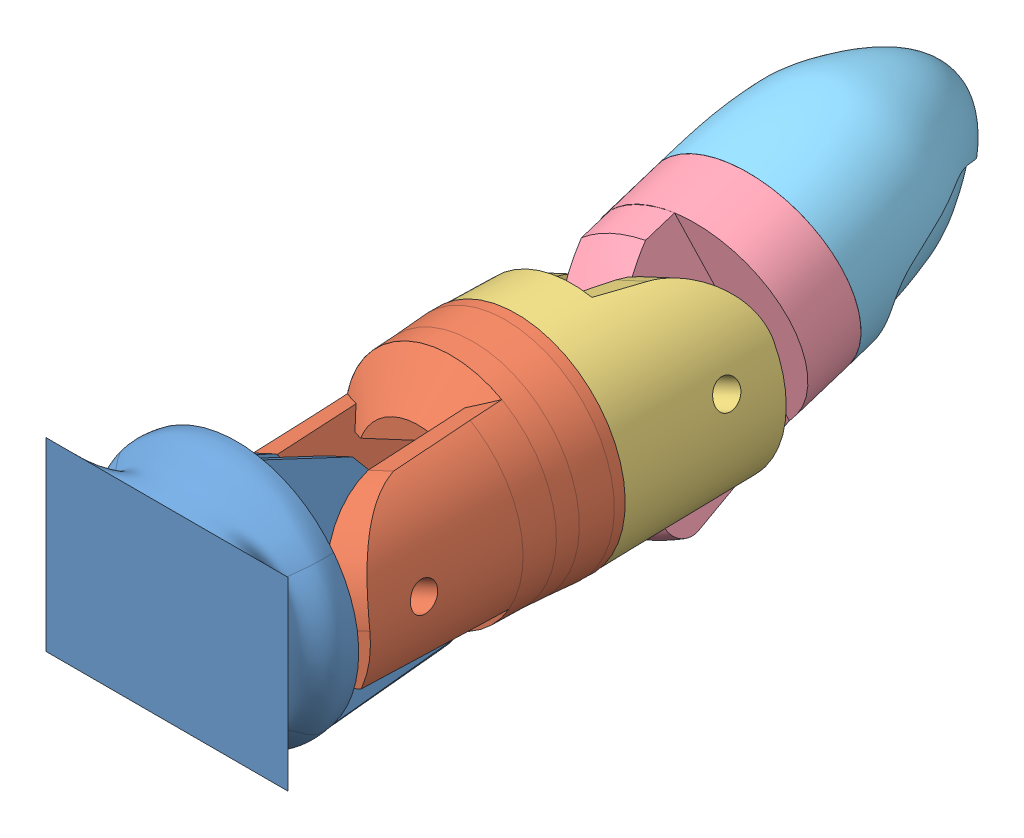
SolidWorks assembly Assem1, configuration Varsayılan. Lengths in mm.
Overall size (28.01 31.96 75.49).
5 component instances, 5 part files, 10 mates.
Components (placement in the parent):
- Thump1-1: Thump1 [Varsayılan] at (66.6015 -4.7425 32.818) size (24.28 22.96 17.51)
- Thump3-1: Thump3 [Varsayılan] at (67.2636 -5.5708 1.8135) x (-0.906308 -0.422618 0) z (-0.000664 0.001423 0.999999) size (20 20 23)
- Thump4-1: Thump4 [Varsayılan] at (67.2736 -5.5923 -13.2662) x (-0.000664 0.001423 0.999999) z (-0.422618 0.906307 -0.00157) size (15.1 20.23 19.9)
- Thump5-1: Thump5 [Varsayılan] at (66.3067 -3.5188 -20.854) x (0.412759 -0.885165 -0.214741) z (0.090753 -0.194621 0.976671) size (19.18 18 18.14)
- Thump6-1: Thump6 [Varsayılan] at (66.3067 -3.5188 -20.854) x (-0.906308 -0.422618 0) z (0.412759 -0.885165 -0.214741) size (18.03 20.34 18.14)
Mates (geometry in assembly coordinates):
- Coincident1: coincident anti-aligned: plane of Thump1-1 through (61.8434 -6.9613 26.818) normal (-0.906308 -0.422618 0); plane of Thump3-1 through (67.767 -19.6644 10.8339) normal (0.906308 0.422618 0)
- Concentric1: concentric aligned: cylinder of Thump1-1 through (62.1293 -11.1237 19.818) axis (0.906308 0.422618 0) radius 1.25; cylinder of Thump3-1 through (56.6915 -13.6594 19.818) axis (0.906308 0.422618 0) radius 1.25
- Coincident2: coincident anti-aligned: plane of Thump3-1 through (67.2636 -5.5708 1.8135) normal (0.000664 -0.001423 -0.999999); plane of Thump4-1 through (87.4996 -8.7415 1.8315) normal (-0.000664 0.001423 0.999999)
- Concentric2: concentric anti-aligned: circle of Thump3-1; circle of Thump4-1
- Coincident4: coincident anti-aligned: plane of Thump4-1 through (70.2191 -4.2188 -13.2662) normal (-0.906308 -0.422618 0); plane of Thump5-1 through (72.0735 -8.1955 -20.5203) normal (0.906308 0.422618 0)
- Concentric3: concentric aligned: cylinder of Thump4-1 through (58.6298 -10.7177 -8.2646) axis (0.906308 0.422618 0) radius 1.25; cylinder of Thump5-1 through (59.5361 -10.2951 -8.2646) axis (0.906308 0.422618 0) radius 1.25
- Coincident5: coincident anti-aligned: plane of Thump5-1 through (66.3067 -3.5188 -20.854) normal (-0.090753 0.194621 -0.976671); plane of Thump6-1 through (60.4157 -6.2659 -20.854) normal (0.090753 -0.194621 0.976671)
- Coincident6: coincident anti-aligned: cylinder of Thump5-1 through (66.8059 -4.5893 -15.4823) axis (-0.090753 0.194621 -0.976671) radius 9; circle of Thump6-1
- Coincident7: coincident anti-aligned: plane of Thump3-1; plane of Thump4-1 through (67.2736 -5.5923 -13.2662) normal (-0.422618 0.906307 -0.00157)
- Coincident8: coincident aligned: plane of Thump5-1; plane of Thump6-1 through (66.3067 -3.5188 -20.854) normal (0.412759 -0.885165 -0.214741)
